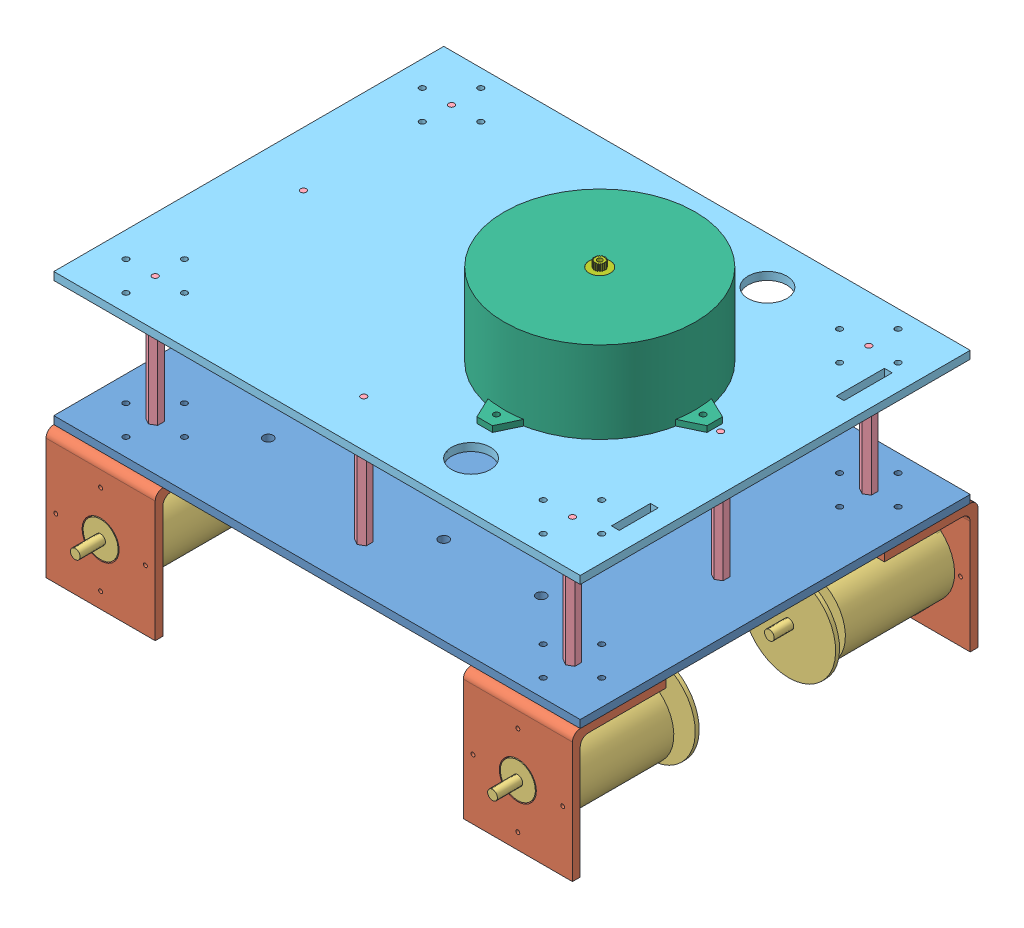
SolidWorks assembly robot - base, configuration Default. Lengths in mm.
Overall size (270 179.13 234).
20 component instances, 7 part files, 37 mates.
Components (placement in the parent):
- base_odroid_down_fix-1: base_odroid_down_fix [Default] at (39.4639 122.941 229.7749) x (1 0 0) z (0 -1 0) size (270 200 4)
- link_motor_1_port-1: link_motor_1_port [Default] at (221.3654 112.3394 287.3354) x (0 0 -1) z (1 0 0) size (48 66 56)
- motor_dc_NISCA-1: motor_dc_NISCA [Default] at (244.2642 39.7289 313.6416) x (0 -1 0) z (0 0 -1) size (54 48 92)
- link_motor_1_port-2: link_motor_1_port [Default] at (221.3654 112.3394 139.9479) x (0 0 1) z (-1 0 0) size (48 66 56)
- motor_dc_NISCA-2: motor_dc_NISCA [Default] at (198.4666 39.7289 113.6416) x (0 -1 0) z (0 0 1) size (54 48 92)
- link_motor_1_port-5: link_motor_1_port [Default] at (7.3654 112.3394 287.3354) x (0 0 -1) z (1 0 0) size (48 66 56)
- motor_dc_NISCA-5: motor_dc_NISCA [Default] at (-15.5334 128.1531 313.6416) x (0 1 0) z (0 0 -1) size (54 48 92)
- link_motor_1_port-6: link_motor_1_port [Default] at (7.3654 112.3394 139.9479) x (0 0 1) z (-1 0 0) size (48 66 56)
- motor_dc_NISCA-6: motor_dc_NISCA [Default] at (-15.5334 39.7289 113.6416) x (0 -1 0) z (0 0 1) size (54 48 92)
- spacer_6cm-2: spacer_6cm [Default] at (221.7099 182.941 288.7798) x (0.5 0 -0.866025) z (0 -1 0) size (6 6.93 68)
- spacer_6cm-3: spacer_6cm [Default] at (114.7099 182.941 288.7798) x (0.5 0 -0.866025) z (0 -1 0) size (6 6.93 68)
- spacer_6cm-4: spacer_6cm [Default] at (7.7099 182.941 288.7798) x (0.5 0 -0.866025) z (0 -1 0) size (6 6.93 68)
- spacer_6cm-5: spacer_6cm [Default] at (221.7099 182.941 212.7798) x (0.5 0 -0.866025) z (0 -1 0) size (6 6.93 68)
- spacer_6cm-7: spacer_6cm [Default] at (7.7099 182.941 212.7798) x (0.5 0 -0.866025) z (0 -1 0) size (6 6.93 68)
- spacer_6cm-8: spacer_6cm [Default] at (221.7099 182.941 136.7798) x (0.5 0 -0.866025) z (0 -1 0) size (6 6.93 68)
- spacer_6cm-9: spacer_6cm [Default] at (114.7099 182.941 136.7798) x (0.5 0 -0.866025) z (0 -1 0) size (6 6.93 68)
- spacer_6cm-10: spacer_6cm [Default] at (7.7099 182.941 136.7798) x (0.5 0 -0.866025) z (0 -1 0) size (6 6.93 68)
- base_odroid_up_fix-1: base_odroid_up_fix [Default] at (186.1287 186.941 197.5083) x (-1 0 0) z (0 -1 0) size (270 200 4)
- base_arm-1: base_arm [Default] at (159.3654 194.0898 219.4289) x (0 0 1) z (-1 0 0) size (118.01 42 118.01)
- servo_hs422-1: servo_hs422 [Default] at (169.6524 210.6756 203.7356) x (0 0 1) z (-1 0 0) size (19.81 42.14 58.23)
Mates (geometry in assembly coordinates):
- Coincident1: coincident anti-aligned: plane of link_motor_1_port-1 through (193.3654 52.941 313.6416) normal (0 0 -1); plane of motor_dc_NISCA-1 through (221.3654 83.941 313.6416) normal (0 0 1)
- Concentric1: concentric aligned: cylinder of link_motor_1_port-1 through (221.3654 83.941 317.6416) axis (0 0 -1) radius 9.5; cylinder of motor_dc_NISCA-1 through (221.3654 83.941 317.6416) axis (0 0 -1) radius 9
- Concentric2: concentric anti-aligned: cylinder of link_motor_1_port-1 through (221.3654 106.941 317.6416) axis (0 0 -1) radius 1; cylinder of motor_dc_NISCA-1 through (221.3654 106.941 311.6416) axis (0 0 1) radius 1.5
- Coincident8: coincident anti-aligned: plane of link_motor_1_port-2 through (249.3654 52.941 113.6416) normal (0 0 1); plane of motor_dc_NISCA-2 through (221.3654 83.941 113.6416) normal (0 0 -1)
- Concentric5: concentric aligned: cylinder of link_motor_1_port-2 through (221.3654 83.941 109.6416) axis (0 0 1) radius 9.5; cylinder of motor_dc_NISCA-2 through (221.3654 83.941 109.6416) axis (0 0 1) radius 9
- Concentric7: concentric anti-aligned: cylinder of link_motor_1_port-2 through (221.3654 106.941 109.6416) axis (0 0 1) radius 1; cylinder of motor_dc_NISCA-2 through (221.3654 106.941 115.6416) axis (0 0 -1) radius 1.5
- Coincident9: coincident anti-aligned: plane of base_odroid_down_fix-1 through (39.4639 118.941 229.7749) normal (0 -1 0); plane of link_motor_1_port-1 through (193.3654 118.941 269.6416) normal (0 1 0)
- Concentric8: concentric anti-aligned: cylinder of base_odroid_down_fix-1 through (206.3654 118.941 289.6416) axis (0 1 0) radius 1.5; cylinder of link_motor_1_port-1 through (206.3654 118.941 289.6416) axis (0 -1 0) radius 1.5
- Concentric9: concentric anti-aligned: cylinder of base_odroid_down_fix-1 through (236.3654 118.941 289.6416) axis (0 1 0) radius 1.5; cylinder of link_motor_1_port-1 through (236.3654 118.941 289.6416) axis (0 -1 0) radius 1.5
- Coincident15: coincident anti-aligned: plane of base_odroid_down_fix-1 through (39.4639 118.941 229.7749) normal (0 -1 0); plane of link_motor_1_port-2 through (249.3654 118.941 157.6416) normal (0 1 0)
- Concentric11: concentric anti-aligned: cylinder of base_odroid_down_fix-1 through (206.3654 118.941 137.6416) axis (0 1 0) radius 1.5; cylinder of link_motor_1_port-2 through (206.3654 118.941 137.6416) axis (0 -1 0) radius 1.5
- Concentric12: concentric anti-aligned: cylinder of base_odroid_down_fix-1 through (236.3654 118.941 137.6416) axis (0 1 0) radius 1.5; cylinder of link_motor_1_port-2 through (236.3654 118.941 137.6416) axis (0 -1 0) radius 1.5
- Coincident16: coincident anti-aligned: plane of link_motor_1_port-5 through (-20.6346 52.941 313.6416) normal (0 0 -1); plane of motor_dc_NISCA-5 through (7.3654 83.941 313.6416) normal (0 0 1)
- Concentric13: concentric aligned: cylinder of link_motor_1_port-5 through (7.3654 83.941 317.6416) axis (0 0 -1) radius 9.5; cylinder of motor_dc_NISCA-5 through (7.3654 83.941 317.6416) axis (0 0 -1) radius 9
- Concentric14: concentric anti-aligned: cylinder of link_motor_1_port-5 through (7.3654 106.941 317.6416) axis (0 0 -1) radius 1; cylinder of motor_dc_NISCA-5 through (7.3654 106.941 311.6416) axis (0 0 1) radius 1.5
- Coincident21: coincident anti-aligned: plane of base_odroid_down_fix-1 through (39.4639 118.941 229.7749) normal (0 -1 0); plane of link_motor_1_port-5 through (-20.6346 118.941 269.6416) normal (0 1 0)
- Concentric17: concentric anti-aligned: cylinder of base_odroid_down_fix-1 through (-7.6346 118.941 289.6416) axis (0 1 0) radius 1.5; cylinder of link_motor_1_port-5 through (-7.6346 118.941 289.6416) axis (0 -1 0) radius 1.5
- Concentric18: concentric anti-aligned: cylinder of base_odroid_down_fix-1 through (22.3654 118.941 289.6416) axis (0 1 0) radius 1.5; cylinder of link_motor_1_port-5 through (22.3654 118.941 289.6416) axis (0 -1 0) radius 1.5
- Coincident22: coincident anti-aligned: plane of link_motor_1_port-6 through (35.3654 52.941 113.6416) normal (0 0 1); plane of motor_dc_NISCA-6 through (7.3654 83.941 113.6416) normal (0 0 -1)
- Concentric19: concentric aligned: cylinder of link_motor_1_port-6 through (7.3654 83.941 109.6416) axis (0 0 1) radius 9.5; cylinder of motor_dc_NISCA-6 through (7.3654 83.941 109.6416) axis (0 0 1) radius 9
- Concentric20: concentric anti-aligned: cylinder of link_motor_1_port-6 through (7.3654 106.941 109.6416) axis (0 0 1) radius 1; cylinder of motor_dc_NISCA-6 through (7.3654 106.941 115.6416) axis (0 0 -1) radius 1.5
- Coincident27: coincident anti-aligned: plane of base_odroid_down_fix-1 through (39.4639 118.941 229.7749) normal (0 -1 0); plane of link_motor_1_port-6 through (35.3654 118.941 157.6416) normal (0 1 0)
- Concentric22: concentric anti-aligned: cylinder of base_odroid_down_fix-1 through (-7.6346 118.941 137.6416) axis (0 1 0) radius 1.5; cylinder of link_motor_1_port-6 through (-7.6346 118.941 137.6416) axis (0 -1 0) radius 1.5
- Concentric23: concentric anti-aligned: cylinder of base_odroid_down_fix-1 through (22.3654 118.941 137.6416) axis (0 1 0) radius 1.5; cylinder of link_motor_1_port-6 through (22.3654 118.941 137.6416) axis (0 -1 0) radius 1.5
- Concentric24: concentric aligned: cylinder of base_odroid_down_fix-1 through (221.3654 118.941 289.6416) axis (0 1 0) radius 1.5; cylinder of spacer_6cm-2 through (221.3654 118.941 289.6416) axis (0 1 0) radius 1.5
- Coincident28: coincident anti-aligned: plane of base_odroid_down_fix-1 through (39.4639 122.941 229.7749) normal (0 1 0); plane of spacer_6cm-2 through (221.7099 122.941 288.7798) normal (0 -1 0)
- Parallel2: parallel aligned: plane of base_odroid_down_fix-1 through (249.3654 118.941 229.7749) normal (1 0 0); plane of spacer_6cm-2 through (224.3654 122.941 287.9096) normal (1 0 0)
- Concentric25: concentric anti-aligned: cylinder of spacer_6cm-2 through (221.3654 186.941 289.6416) axis (0 -1 0) radius 1.5; cylinder of base_odroid_up_fix-1 through (221.3654 182.941 289.6416) axis (0 1 0) radius 1.5
- Concentric26: concentric anti-aligned: cylinder of spacer_6cm-7 through (7.3654 186.941 213.6416) axis (0 -1 0) radius 1.5; cylinder of base_odroid_up_fix-1 through (7.3654 182.941 213.6416) axis (0 1 0) radius 1.5
- Coincident29: coincident anti-aligned: plane of spacer_6cm-2 through (221.7099 182.941 288.7798) normal (0 1 0); plane of base_odroid_up_fix-1 through (186.1287 182.941 197.5083) normal (0 -1 0)
- Coincident31: coincident anti-aligned: plane of base_arm-1 through (159.3654 225.941 213.6416) normal (0 -1 0); plane of servo_hs422-1 through (169.6524 225.941 203.7356) normal (0 1 0)
- Parallel3: parallel aligned: plane of base_odroid_up_fix-1 through (249.3654 182.941 197.5083) normal (1 0 0); plane of servo_hs422-1 through (189.5914 210.6756 223.5476) normal (1 0 0)
- Coincident33: coincident anti-aligned: plane of base_odroid_up_fix-1 through (186.1287 186.941 197.5083) normal (0 1 0); plane of base_arm-1 through (159.3654 186.941 259.6416) normal (0 -1 0)
- Concentric28: concentric anti-aligned: cylinder of base_odroid_up_fix-1 through (212.3654 182.941 213.6416) axis (0 1 0) radius 1.5; cylinder of base_arm-1 through (212.3654 189.941 213.6416) axis (0 -1 0) radius 1.5
- Concentric29: concentric anti-aligned: cylinder of base_odroid_up_fix-1 through (159.3654 182.941 160.6416) axis (0 1 0) radius 1.5; cylinder of base_arm-1 through (159.3654 189.941 160.6416) axis (0 -1 0) radius 1.5
- Parallel5: parallel aligned: plane of base_odroid_up_fix-1 through (186.1287 182.941 113.6416) normal (0 0 -1); plane of servo_hs422-1 through (169.6524 210.6756 203.7356) normal (0 0 -1)
- Concentric30: concentric aligned: cylinder of base_arm-1 through (159.3654 225.941 213.6416) axis (0 1 0) radius 5.4623; cylinder of servo_hs422-1 through (159.3654 202.0734 213.6416) axis (0 1 0) radius 6.4897
